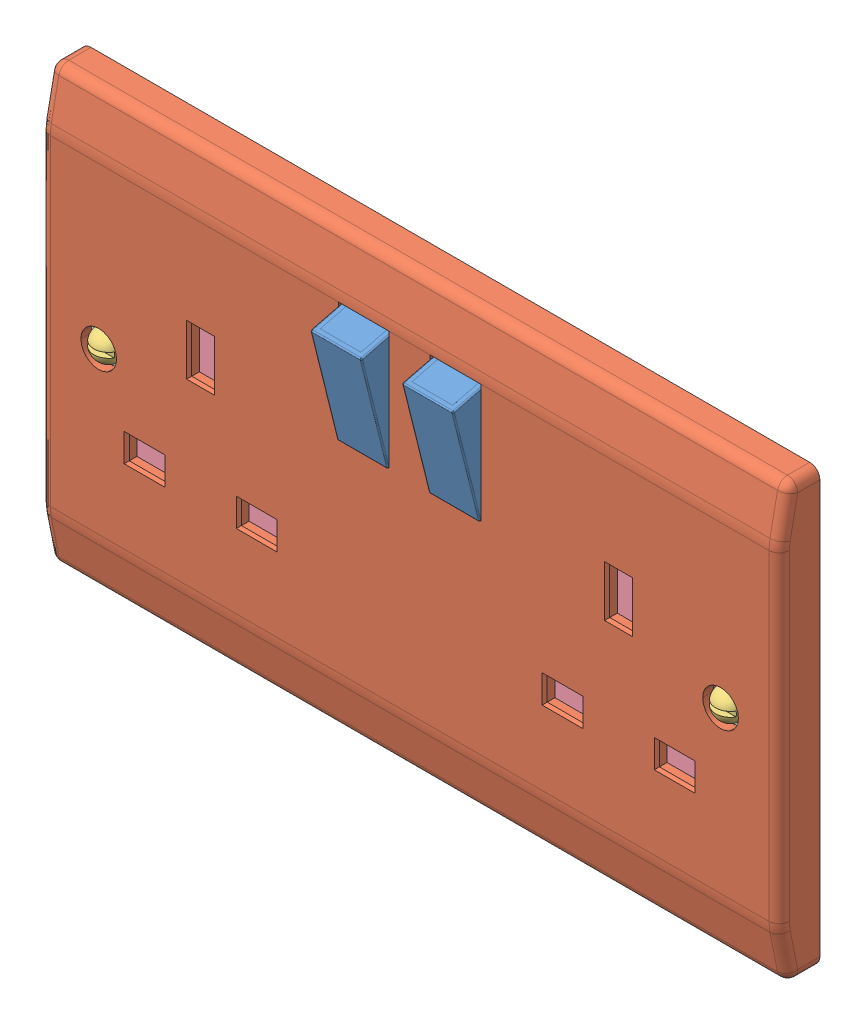
SolidWorks assembly Assembled Mains Plug Socket, configuration Default. Lengths in mm.
Overall size (145 85 22).
8 component instances, 4 part files, 0 mates.
Components (placement in the parent):
- Assembled Mains Plug Socket.STEP-1: Assembled Mains Plug Socket.STEP [Default] at origin size (145 85 22)
  - Switch.STEP-1: Switch.STEP [Default] at (4 10.2944 -0.5423) x (1 0 0) z (0 -0.970296 -0.241922) size (14 10 26)
  - Base Plate.STEP-1: Base Plate.STEP [Default] at origin size (145 85 8)
  - Switch.STEP-2: Switch.STEP [Default] at (-14 10.2944 -0.5423) x (1 0 0) z (0 -0.970296 -0.241922) size (14 10 26)
  - Screw.STEP-1: Screw.STEP [Default] at (61 0 -8) x (1 0 0) z (0 -1 0) size (6 16.96 6)
  - Screw.STEP-2: Screw.STEP [Default] at (-61 0 -8) x (1 0 0) z (0 -1 0) size (6 16.96 6)
  - Black Cover.STEP-1: Black Cover.STEP [Default] at (-56 -22 1) x (1 0 0) z (0 -1 0) size (30 5 40)
  - Black Cover.STEP-2: Black Cover.STEP [Default] at (26 -22 1) x (1 0 0) z (0 -1 0) size (30 5 40)
